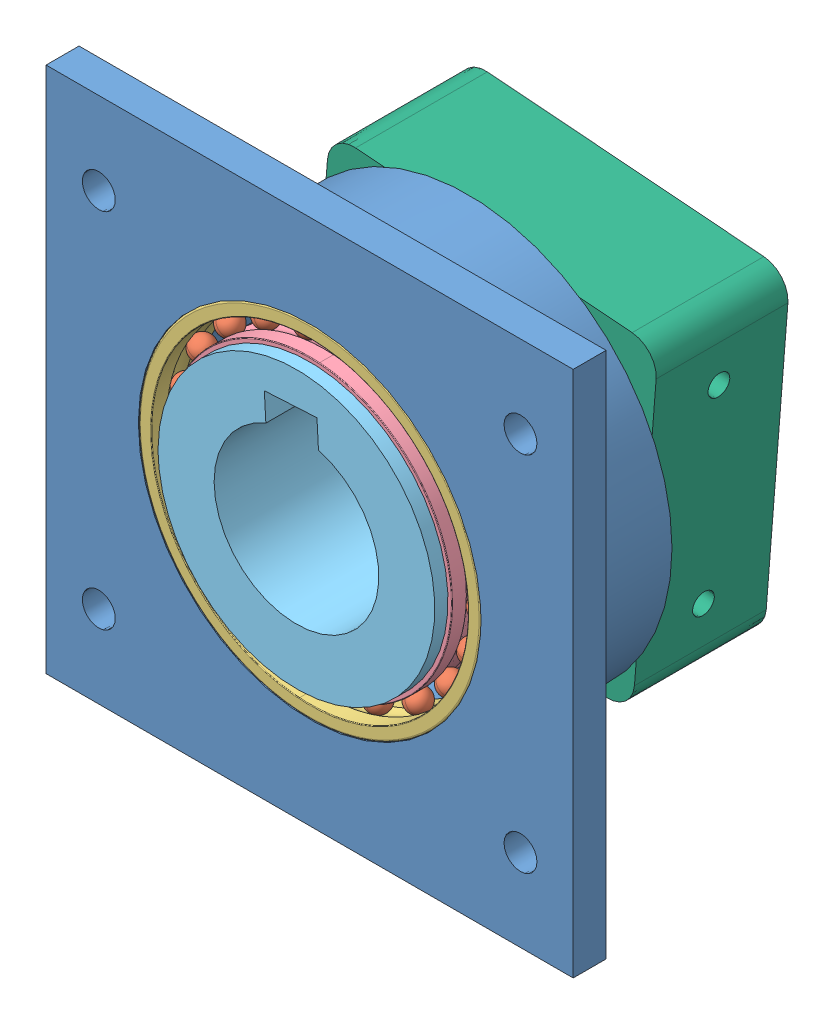
SolidWorks assembly Forearm mounting assembly, configuration Default. Lengths in mm.
Overall size (80 80 48).
51 component instances, 6 part files, 8 mates.
Components (placement in the parent):
- Forearm mount-1: Forearm mount [Default] at (23.4598 35.5842 33.2293) size (80 80 24)
- 61808-1: 61808 [Default] at (23.4598 35.5842 50.2293) x (0 0 1) z (0.066698 0.997773 0) size (7 52 52)
  - 61808_25-1: 61808_25 [Default] x (1 0 0) z (0 -0.294755 0.955573) size (3.5 3.5 3.5)
  - 61808_25-2: 61808_25 [Default] x (1 0 0) z (0 -0.56332 0.826239) size (3.5 3.5 3.5)
  - 61808_25-3: 61808_25 [Default] x (1 0 0) z (0 -0.781831 0.62349) size (3.5 3.5 3.5)
  - 61808_25-4: 61808_25 [Default] x (1 0 0) z (0 -0.930874 0.365341) size (3.5 3.5 3.5)
  - 61808_25-5: 61808_25 [Default] x (1 0 0) z (0 -0.997204 0.07473) size (3.5 3.5 3.5)
  - 61808_25-6: 61808_25 [Default] x (1 0 0) z (0 -0.974928 -0.222521) size (3.5 3.5 3.5)
  - 61808_25-7: 61808_25 [Default] x (1 0 0) z (0 -0.866025 -0.5) size (3.5 3.5 3.5)
  - 61808_25-8: 61808_25 [Default] x (1 0 0) z (0 -0.680173 -0.733052) size (3.5 3.5 3.5)
  - 61808_25-9: 61808_25 [Default] x (1 0 0) z (0 -0.433884 -0.900969) size (3.5 3.5 3.5)
  - 61808_25-10: 61808_25 [Default] x (1 0 0) z (0 -0.149042 -0.988831) size (3.5 3.5 3.5)
  - 61808_25-11: 61808_25 [Default] x (1 0 0) z (0 0.149042 -0.988831) size (3.5 3.5 3.5)
  - 61808_25-12: 61808_25 [Default] x (1 0 0) z (0 0.433884 -0.900969) size (3.5 3.5 3.5)
  - 61808_25-13: 61808_25 [Default] x (1 0 0) z (0 0.680173 -0.733052) size (3.5 3.5 3.5)
  - 61808_25-14: 61808_25 [Default] x (1 0 0) z (0 0.866025 -0.5) size (3.5 3.5 3.5)
  - 61808_25-15: 61808_25 [Default] x (1 0 0) z (0 0.974928 -0.222521) size (3.5 3.5 3.5)
  - 61808_25-16: 61808_25 [Default] x (1 0 0) z (0 0.997204 0.07473) size (3.5 3.5 3.5)
  - 61808_25-17: 61808_25 [Default] x (1 0 0) z (0 0.930874 0.365341) size (3.5 3.5 3.5)
  - 61808_25-18: 61808_25 [Default] x (1 0 0) z (0 0.781831 0.62349) size (3.5 3.5 3.5)
  - 61808_25-19: 61808_25 [Default] x (1 0 0) z (0 0.56332 0.826239) size (3.5 3.5 3.5)
  - 61808_25-20: 61808_25 [Default] x (1 0 0) z (0 0.294755 0.955573) size (3.5 3.5 3.5)
  - 61808_25-21: 61808_25 [Default] at origin size (3.5 3.5 3.5)
  - 61808_47-1: 61808_47 [Default] at origin size (7 52 52)
  - 61808_49-1: 61808_49 [Default] at origin size (7 43.21 43.21)
- 61808-2: 61808 [Default] at (23.4598 35.5842 33.2293) x (0 0 1) z (-0.983327 0.181844 0) size (7 52 52)
  - 61808_25-1: 61808_25 [Default] x (1 0 0) z (0 -0.294755 0.955573) size (3.5 3.5 3.5)
  - 61808_25-2: 61808_25 [Default] x (1 0 0) z (0 -0.56332 0.826239) size (3.5 3.5 3.5)
  - 61808_25-3: 61808_25 [Default] x (1 0 0) z (0 -0.781831 0.62349) size (3.5 3.5 3.5)
  - 61808_25-4: 61808_25 [Default] x (1 0 0) z (0 -0.930874 0.365341) size (3.5 3.5 3.5)
  - 61808_25-5: 61808_25 [Default] x (1 0 0) z (0 -0.997204 0.07473) size (3.5 3.5 3.5)
  - 61808_25-6: 61808_25 [Default] x (1 0 0) z (0 -0.974928 -0.222521) size (3.5 3.5 3.5)
  - 61808_25-7: 61808_25 [Default] x (1 0 0) z (0 -0.866025 -0.5) size (3.5 3.5 3.5)
  - 61808_25-8: 61808_25 [Default] x (1 0 0) z (0 -0.680173 -0.733052) size (3.5 3.5 3.5)
  - 61808_25-9: 61808_25 [Default] x (1 0 0) z (0 -0.433884 -0.900969) size (3.5 3.5 3.5)
  - 61808_25-10: 61808_25 [Default] x (1 0 0) z (0 -0.149042 -0.988831) size (3.5 3.5 3.5)
  - 61808_25-11: 61808_25 [Default] x (1 0 0) z (0 0.149042 -0.988831) size (3.5 3.5 3.5)
  - 61808_25-12: 61808_25 [Default] x (1 0 0) z (0 0.433884 -0.900969) size (3.5 3.5 3.5)
  - 61808_25-13: 61808_25 [Default] x (1 0 0) z (0 0.680173 -0.733052) size (3.5 3.5 3.5)
  - 61808_25-14: 61808_25 [Default] x (1 0 0) z (0 0.866025 -0.5) size (3.5 3.5 3.5)
  - 61808_25-15: 61808_25 [Default] x (1 0 0) z (0 0.974928 -0.222521) size (3.5 3.5 3.5)
  - 61808_25-16: 61808_25 [Default] x (1 0 0) z (0 0.997204 0.07473) size (3.5 3.5 3.5)
  - 61808_25-17: 61808_25 [Default] x (1 0 0) z (0 0.930874 0.365341) size (3.5 3.5 3.5)
  - 61808_25-18: 61808_25 [Default] x (1 0 0) z (0 0.781831 0.62349) size (3.5 3.5 3.5)
  - 61808_25-19: 61808_25 [Default] x (1 0 0) z (0 0.56332 0.826239) size (3.5 3.5 3.5)
  - 61808_25-20: 61808_25 [Default] x (1 0 0) z (0 0.294755 0.955573) size (3.5 3.5 3.5)
  - 61808_25-21: 61808_25 [Default] at origin size (3.5 3.5 3.5)
  - 61808_47-1: 61808_47 [Default] at origin size (7 52 52)
  - 61808_49-1: 61808_49 [Default] at origin size (7 43.21 43.21)
- Forearm shaft coupler-1: Forearm shaft coupler [Default] at (23.4598 35.5842 59.2293) x (-0.998478 -0.055153 0) z (0 0 -1) size (42 42 48)
- Forearm housing-1: Forearm housing [Default] at (23.4598 35.5842 11.2293) x (0.996937 -0.078212 0) z (0 0 1) size (50.04 50.04 22)
Mates (geometry in assembly coordinates):
- Concentric1: concentric anti-aligned: cylinder of Forearm mount-1 through (23.4598 35.5842 57.2293) axis (0 0 -1) radius 26; cylinder of 61808-1/61808_49-1 through (23.4598 35.5842 150.2293) axis (0 0 1) radius 20
- Distance1: distance = 0 mm anti-aligned: plane of Forearm mount-1 through (23.4598 35.5842 50.2293) normal (0 0 1); plane of 61808-1/61808_47-1 through (49.1026 33.87 50.2293) normal (0 0 -1)
- Concentric2: concentric anti-aligned: cylinder of Forearm mount-1 through (23.4598 35.5842 40.2293) axis (0 0 -1) radius 26; cylinder of 61808-2/61808_49-1 through (23.4598 35.5842 133.2293) axis (0 0 1) radius 20
- Distance2: distance = 0 mm anti-aligned: plane of Forearm mount-1 through (23.4598 35.5842 40.2293) normal (0 0 -1); plane of 61808-2/61808_47-1 through (27.8513 59.3315 40.2293) normal (0 0 1)
- Concentric3: concentric anti-aligned: cylinder of Forearm mount-1 through (23.4598 35.5842 50.2293) axis (0 0 -1) radius 25; cylinder of Forearm shaft coupler-1 through (23.4598 35.5842 11.2293) axis (0 0 1) radius 12.5
- Coincident1: coincident anti-aligned: plane of 61808-1/61808_49-1 through (43.7146 34.2302 57.2293) normal (0 0 1); plane of Forearm shaft coupler-1 through (23.4598 35.5842 57.2293) normal (0 0 -1)
- Concentric5: concentric anti-aligned: cylinder of Forearm shaft coupler-1 through (23.4598 35.5842 11.2293) axis (0 0 1) radius 20; cylinder of Forearm housing-1 through (23.4598 35.5842 31.2293) axis (0 0 -1) radius 20
- Coincident3: coincident anti-aligned: plane of 61808-2/61808_49-1 through (27.3703 56.7306 33.2293) normal (0 0 -1); plane of Forearm housing-1 through (23.4598 35.5842 33.2293) normal (0 0 1)
